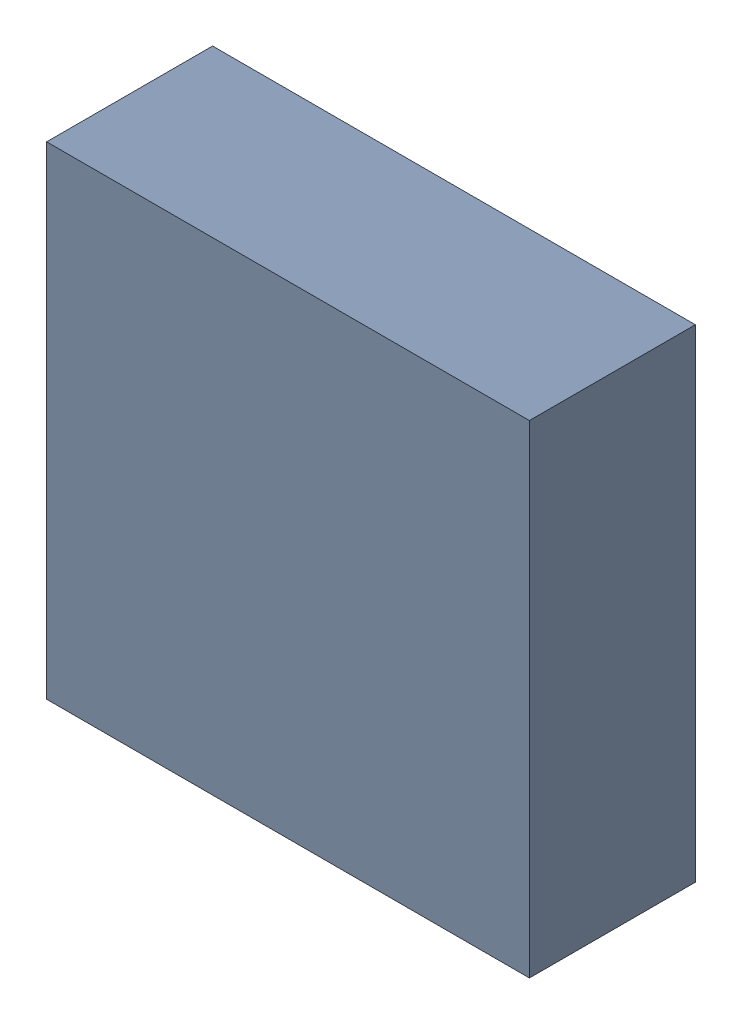
SolidWorks assembly U303_1PCB, configuration Default. Lengths in mm.
Overall size (3.2 3.2 1.1).
2 component instances, 1 part files, 0 mates.
Components (placement in the parent):
- 846484240-1: 846484240 [Default] at (141.3 106.7 0) size (3.2 3.2 1.1)
  - Extruded_11-1: Extruded_11 [Default] at origin size (3.2 3.2 1.1)
